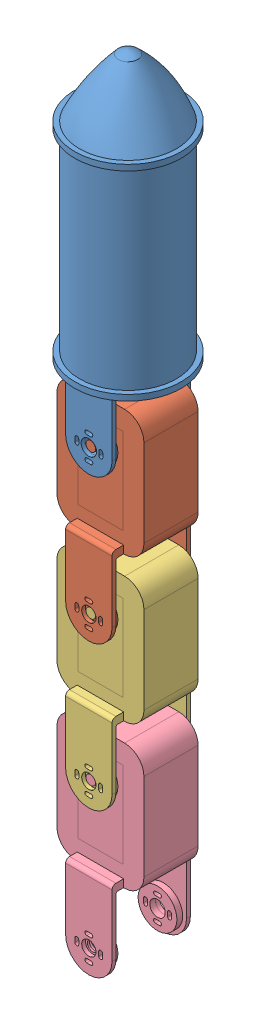
SolidWorks assembly test3, configuration 預設. Lengths in mm.
Overall size (55 404.08 55).
4 component instances, 4 part files, 16 mates.
Components (placement in the parent):
- base_link2-2: base_link2 [預設] at origin size (55 179.98 55)
- link1-1: link1 [預設] at (0 -157.7 0) x (0 1 0) z (0 0 -1) size (107 45 40.5)
- link2-1: link2 [預設] at (0 -232.4 0) x (0 1 0) z (0 0 -1) size (107 45 40.5)
- link3-2: link3 [預設] at (0 -307.1 0) x (0 1 0) z (0 0 -1) size (107 45 40.5)
Mates (geometry in assembly coordinates):
- 平行相距4: distance = 18.5 mm: plane of base_link2-2 through (0 -83 -18.5) normal (0 0 1); plane of assembly through (0 0 0) normal (0 0 1)
- 平行相距5: distance = 12 mm: plane of assembly through (0 0 0) normal (1 0 0); plane of base_link2-2 through (12 -53 18) normal (1 0 0)
- 平行相距6: distance = 50 mm: plane of assembly through (0 0 0) normal (0 1 0); plane of base_link2-2 through (0 -50 -0.25) normal (0 1 0)
- 同軸心2: concentric: cylinder of base_link2-2 through (0 -83 18) axis (0 0 1) radius 4; cylinder of link1-1 through (0 -83 14) axis (0 0 1) radius 2.5
- 同軸心3: concentric: cylinder of base_link2-2 through (0 -83 -20.5) axis (0 0 1) radius 4; cylinder of link1-1 through (0 -83 -19) axis (0 0 1) radius 2.5
- 平行1: parallel: plane of base_link2-2 through (12 -53 -20.5) normal (1 0 0); plane of link1-1 through (22.5 -127.7 -14) normal (1 0 0)
- 重合/共線/共點8: coincident: plane of base_link2-2 through (0 -83 -18.5) normal (0 0 1); plane of link1-1 through (0 -157.7 -18.5) normal (0 0 1)
- 同軸心4: concentric: cylinder of link1-1 through (0 -157.7 20) axis (0 0 -1) radius 3.7; cylinder of ? through (122.3295 -185.6512 7.75) axis (0 0 -1) radius 2.5
- 重合/共線/共點9: coincident: plane of link1-1 through (22.5 -127.7 -14) normal (1 0 0); unknown of ?
- 重合/共線/共點10: coincident: plane of link1-1 through (0 -67.7653 20) normal (0 0 1); line of ? through (137.5641 -185.6512 1.75) axis (0 0 -1)
- 重合/共線/共點11: coincident: plane of link1-1 through (22.5 -127.7 -14) normal (1 0 0); plane of link2-1 through (22.5 -202.4 -14) normal (1 0 0)
- 同軸心5: concentric: cylinder of link1-1 through (0 -157.7 20) axis (0 0 -1) radius 3.7; cylinder of link2-1 through (0 -157.7 14) axis (0 0 1) radius 2.5
- 重合/共線/共點12: coincident: plane of link1-1 through (0 -67.7653 14) normal (0 0 1); plane of link2-1 through (0 -142.4653 14) normal (0 0 1)
- 重合/共線/共點14: coincident: plane of link2-1 through (22.5 -202.4 -14) normal (1 0 0); plane of link3-2 through (22.5 -277.1 -14) normal (1 0 0)
- 同軸心6: concentric: cylinder of link2-1 through (0 -232.4 -18.5) axis (0 0 -1) radius 4; cylinder of link3-2 through (0 -232.4 -19) axis (0 0 1) radius 2.5; plane of link2-1; plane of link3-2
- 重合/共線/共點15: coincident: plane of link2-1 through (0 -142.4653 -14) normal (0 0 -1); plane of link3-2 through (0 -217.1653 -14) normal (0 0 -1)
